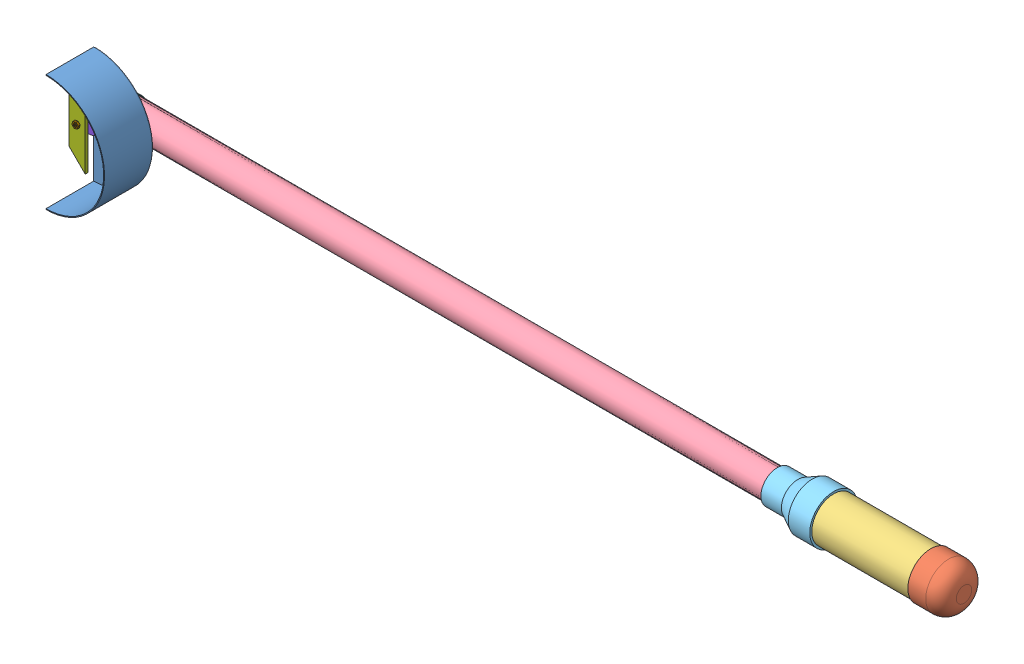
SolidWorks assembly Assem3, configuration Default. Lengths in mm.
Overall size (1560.78 211 164.44).
9 component instances, 9 part files, 14 mates.
Components (placement in the parent):
- shield-1: shield [Default] at (-1651.3693 -131.9873 -90.0097) size (105.5 211 88)
- cap 3in-1: cap 3in [Default] at (-158.6725 -26.4873 -125.3472) size (59.91 82.86 82.86)
- D79 pipe-1: D79 pipe [Default] at (-166.9185 -26.4873 -125.3472) x (0 0 1) z (-1 0 0) size (79 79 200)
- D50+8-1: D50+8 [Default] at (-1623.7721 -26.4873 -125.3472) size (1192 50.8 50.8)
- reduced coupling 3x2in-1: reduced coupling 3x2in [Default] at (-352.3001 -26.4873 -125.3472) x (-1 0 0) z (0 0 -1) size (101.6 86.2 86.2)
- 2in elbow-1: 2in elbow [Default] at (-1651.3693 -26.4873 -116.4151) size (59.98 53.28 59.98)
- blade-1: blade [Default] at (-1574.5908 -43.7985 -60.1716) x (1 0 0) z (0 1 0) size (29 5 142)
- motor-1: motor [Default] at (-1651.3693 -26.4873 -110.1716) x (1 0 0) z (0 -1 0) size (50 50 50)
- m6 nut-1: m6 nut [Default] at (-1651.3693 -26.4873 -61.2961) x (1 0 0) z (0 -1 0) size (11.27 5.3 11.02)
Mates (geometry in assembly coordinates):
- Concentric2: concentric aligned: cylinder of D79 pipe-1 through (-366.9185 -26.4873 -125.3472) axis (1 0 0) radius 39.5; cylinder of reduced coupling 3x2in-1 through (-352.3001 -26.4873 -125.3472) axis (1 0 0) radius 38.1
- Concentric3: concentric anti-aligned: cylinder of D50+8-1 through (-431.7721 -26.4873 -125.3472) axis (-1 0 0) radius 25.4; cylinder of reduced coupling 3x2in-1 through (-352.3001 -26.4873 -125.3472) axis (1 0 0) radius 29.656
- Lock1: lock: unknown of D50+8-1; unknown of reduced coupling 3x2in-1
- Lock2: lock: unknown of D79 pipe-1; unknown of reduced coupling 3x2in-1
- Concentric4: concentric anti-aligned: cylinder of D50+8-1 through (-431.7721 -26.4873 -125.3472) axis (-1 0 0) radius 25.4; cylinder of 2in elbow-1 through (-1680.7726 -26.4873 -125.3472) axis (1 0 0) radius 26.6393
- Lock3: lock: unknown of D50+8-1; unknown of 2in elbow-1
- Concentric5: concentric aligned: circle of shield-1; cylinder of 2in elbow-1 through (-1651.3693 -26.4873 -92.0097) axis (0 0 -1) radius 26.6393
- Concentric6: concentric anti-aligned: cylinder of cap 3in-1 through (-158.6725 -26.4873 -125.3472) axis (-1 0 0) radius 41.4279; cylinder of D79 pipe-1 through (-366.9185 -26.4873 -125.3472) axis (1 0 0) radius 39.5
- Lock4: lock: unknown of cap 3in-1; unknown of D79 pipe-1
- Concentric8: concentric aligned: circle of 2in elbow-1; cylinder of motor-1 through (-1651.3693 -26.4873 -80.1716) axis (0 0 -1) radius 25
- Lock5: lock: unknown of 2in elbow-1; unknown of motor-1
- Concentric9: concentric anti-aligned: cylinder of blade-1 through (-1651.3693 -26.4873 -65.1716) axis (0 0 1) radius 2; cylinder of motor-1 through (-1651.3693 -26.4873 -60.1716) axis (0 0 -1) radius 1.5
- Coincident1: coincident aligned: plane of blade-1 through (-1574.5908 -43.7985 -60.1716) normal (0 0 1); plane of motor-1 through (-1651.3693 -26.4873 -60.1716) normal (0 0 1)
- Concentric10: concentric anti-aligned: circle of blade-1; circle of m6 nut-1
